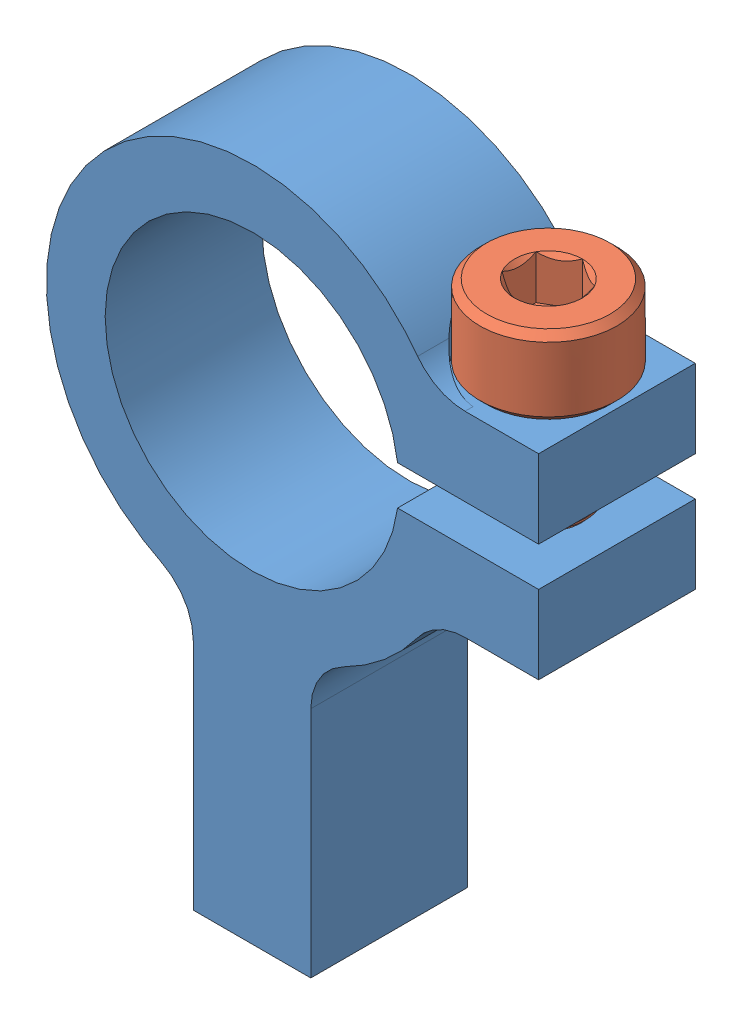
SolidWorks assembly 1-Side, 1-Post Clamping Mount (15mm Bore) 1403-0024-0015, configuration Default. Lengths in mm.
Overall size (25.13 34.5 8).
2 component instances, 2 part files, 0 mates.
Components (placement in the parent):
- 1403-0024-0015 without hardware.step-1: 1403-0024-0015 without hardware.step [Default] at (-16.1228 -1.8908 -4.9663) size (25.13 34.5 8)
- 2800-0004-0010.step-1: 2800-0004-0010.step [Default] at (-4.9897 -6.8908 -0.9663) size (7 14.01 7)
